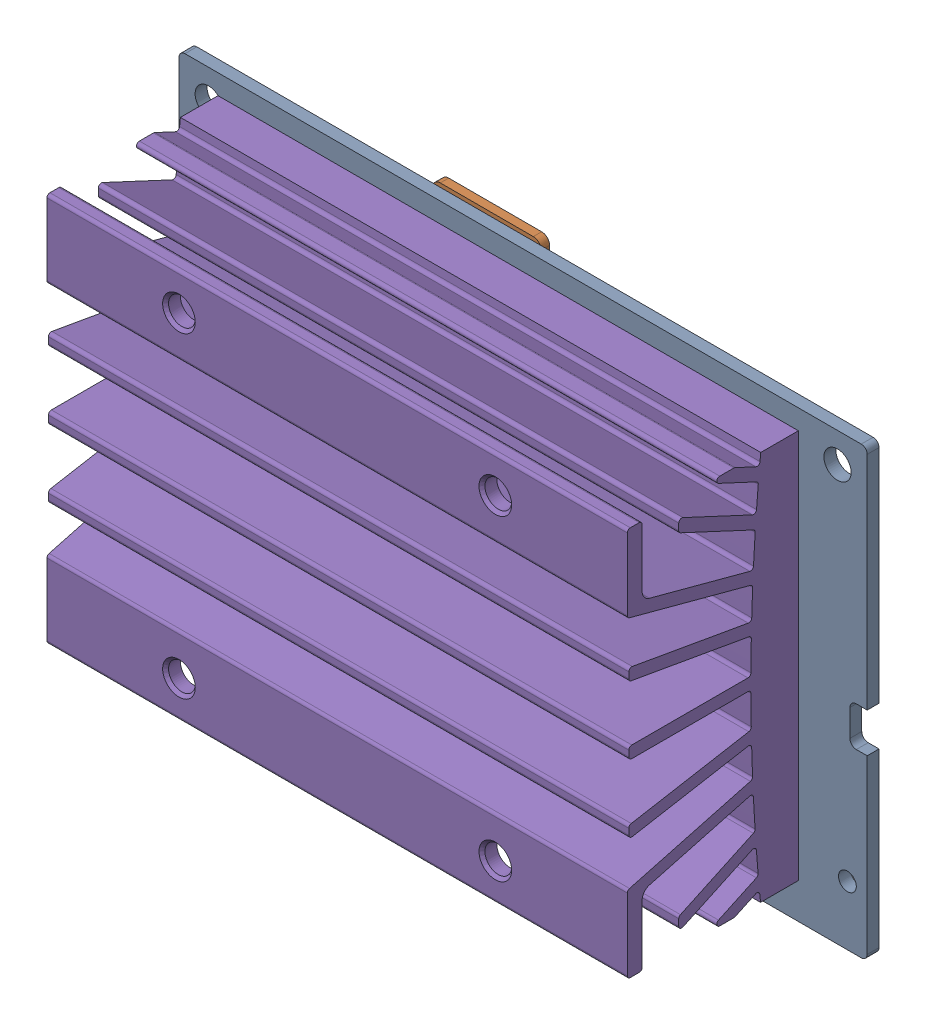
SolidWorks assembly 244-63448-0000-000_ASM, configuration Défaut. Lengths in mm.
Overall size (69.6 45 21.37).
13 component instances, 6 part files, 0 mates.
Components (placement in the parent):
- 142-63448-1GEN_A00-1: 142-63448-1GEN_A00 [Défaut] at origin size (69.6 45 1.2)
- 142-13448-1000-A02_ASM-1: 142-13448-1000-A02_ASM [Défaut] at origin size (23 37.02 4.04)
  - 080-0051-000_3-1: 080-0051-000_3 [Défaut] at (28.331 29.139 0) x (-1 0 0) z (0 0 -1) size (13.4 17 1.29)
  - TM670M-A2_1-1: TM670M-A2_1 [Défaut] at (23.7 13.45 1.2) size (23 23 1.31)
- 142-13448-1000-A02-SKU0000_ASM-1: 142-13448-1000-A02-SKU0000_ASM [Défaut] at origin size (23 23 1.31)
  - TM670M-A2_1-1: TM670M-A2_1 [Défaut] at (23.7 13.45 1.2) size (23 23 1.31)
- PORG_HSK_ASSY_ASM-1: PORG_HSK_ASSY_ASM [Défaut] at (0 0 4.01) size (58.7 39.4 17.3)
  - PORG_HEAT_SINK-1: PORG_HEAT_SINK [Défaut] at origin size (58.7 39.4 17.3)
- PORG_LEAF_SPRING_DRAWN-1: PORG_LEAF_SPRING_DRAWN [Défaut] at (0 0 -0.4) x (1 0.000001 0) z (0 0 1) size (39.83 21.3 1.2)
- PORG_LEAF_SPRING_SCREW-1: PORG_LEAF_SPRING_SCREW [Défaut] at (6.9871 5.9982 5.21) x (0 0 -1) z (0 1 0) size (6.41 4.7 4.7)
- PORG_LEAF_SPRING_SCREW-2: PORG_LEAF_SPRING_SCREW [Défaut] at (6.9871 20.9018 5.21) x (0 0 -1) z (0 1 0) size (6.41 4.7 4.7)
- PORG_LEAF_SPRING_SCREW-3: PORG_LEAF_SPRING_SCREW [Défaut] at (40.4129 20.9018 5.21) x (0 0 -1) z (0 1 0) size (6.41 4.7 4.7)
- PORG_LEAF_SPRING_SCREW-4: PORG_LEAF_SPRING_SCREW [Défaut] at (40.4129 5.9982 5.21) x (0 0 -1) z (0 1 0) size (6.41 4.7 4.7)
